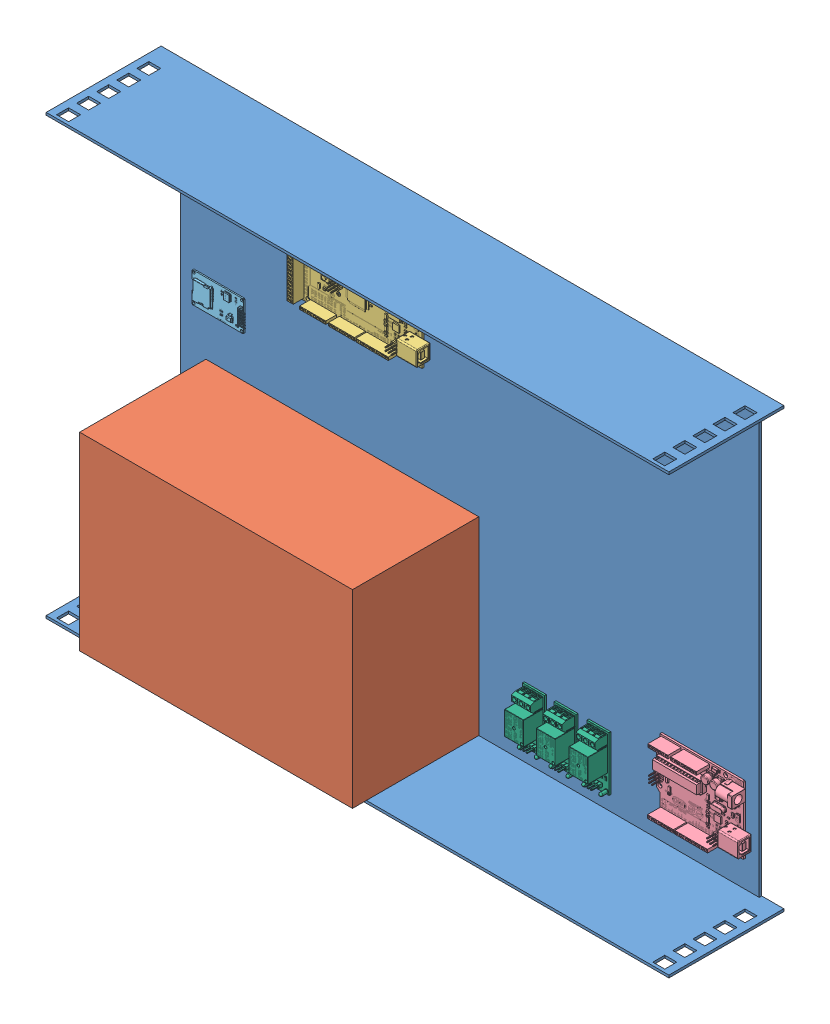
SolidWorks assembly Assem1, configuration Default. Lengths in mm.
Overall size (493 347 102).
8 component instances, 6 part files, 6 mates.
Components (placement in the parent):
- Tray-1: Tray [Default] at (-104.4971 -481.776 176.9252) size (493 347 91)
- Battery-1: Battery [Default] at (-313.4971 -503.276 278.9252) x (0 -1 0) z (0 0 -1) size (150 216 100)
- Arduino MEGA 2560 R3-1: Arduino MEGA 2560 R3 [Default] at (-191.6419 -395.7914 180.5252) x (0 -1 0) z (-1 0 0) size (53.6 14.61 108.35)
- Arduino UNO R3-1: Arduino UNO R3 [Default] at (79.2302 -605.3027 180.5252) x (0 -1 0) z (-1 0 0) size (53.3 14.61 75.28)
- SD Card module-1: SD Card module [Valor predeterminado] at (-303.1095 -458.1771 178.9252) x (-1 0 0) z (0 1 0) size (44.75 4 24)
- Arduino relay 01-2: Arduino relay 01 [Valor predeterminado] at (-42.156 -609.378 189.4502) x (0 -1 0) z (-1 0 0) size (43 18.35 17.5)
- Arduino relay 01-3: Arduino relay 01 [Valor predeterminado] at (-17.1206 -609.8442 189.4502) x (0 -1 0) z (-1 0 0) size (43 18.35 17.5)
- Arduino relay 01-4: Arduino relay 01 [Valor predeterminado] at (8.866 -609.3602 189.4502) x (0 -1 0) z (-1 0 0) size (43 18.35 17.5)
Mates (geometry in assembly coordinates):
- Coincident1: coincident anti-aligned: plane of Tray-1 through (-104.4971 -481.776 178.9252) normal (0 0 1); plane of Battery-1 through (-313.4971 -503.276 178.9252) normal (0 0 -1)
- Distance2: distance = 20 mm aligned: plane of Tray-1 through (-333.4971 -655.276 178.9252) normal (-1 0 0); plane of Battery-1 through (-313.4971 -503.276 178.9252) normal (-1 0 0)
- Distance1: distance = 0 mm anti-aligned: plane of Battery-1 through (-313.4971 -653.276 178.9252) normal (0 -1 0); plane of Tray-1 through (-104.4971 -653.276 176.9252) normal (0 1 0)
- Coincident5: coincident anti-aligned: plane of Tray-1 through (-104.4971 -481.776 178.9252) normal (0 0 1); plane of Arduino UNO R3-1 through (79.2302 -605.3027 178.9252) normal (0 0 -1)
- Coincident6: coincident anti-aligned: plane of Tray-1 through (-104.4971 -481.776 178.9252) normal (0 0 1); plane of Arduino MEGA 2560 R3-1 through (-191.6419 -395.7914 178.9252) normal (0 0 -1)
- Coincident7: coincident anti-aligned: plane of Tray-1 through (-104.4971 -481.776 178.9252) normal (0 0 1); plane of SD Card module-1 through (-303.1095 -458.1771 178.9252) normal (0 0 -1)
